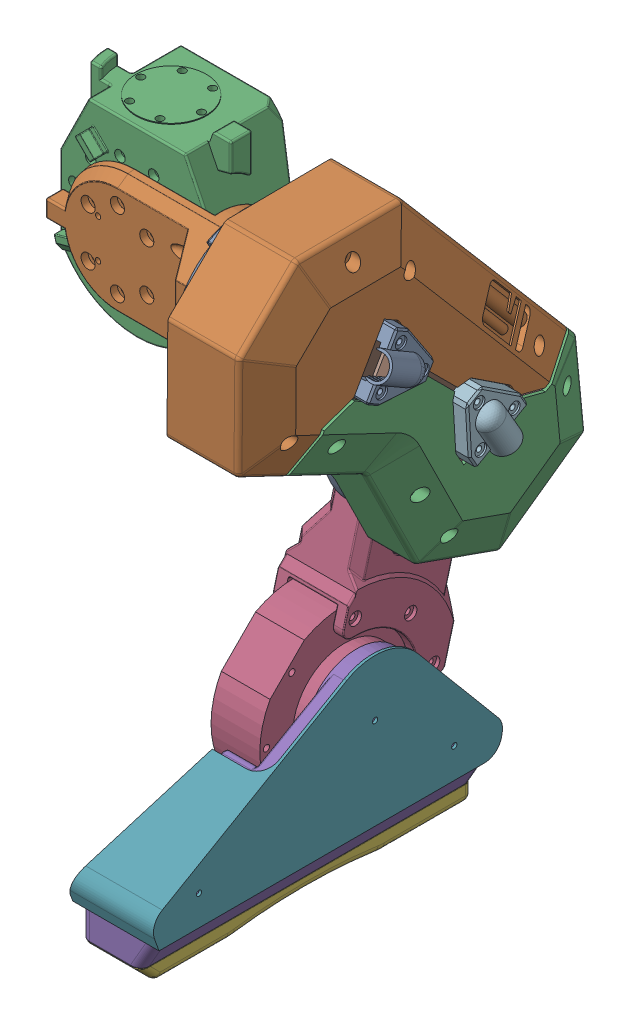
SolidWorks assembly 左腿, configuration 默认. Lengths in mm.
Overall size (184.93 459.26 275.12).
15 component instances, 12 part files, 51 mates.
Components (placement in the parent):
- 大腿left_pitch-1: 大腿left_pitch [默认] at (63 -62.5711 -79.7817) x (0 -0.707107 -0.707107) z (1 0 0) size (220 100.08 52.07)
- 大腿left_roll-1: 大腿left_roll [默认] at (63 -55.5 -2) x (0 0 1) z (-1 0 0) size (71.94 70 103.87)
- 大腿left_yaw-1: 大腿left_yaw [默认] at (0 -55.5 -53) size (99.54 110 58)
- 小腿left_pitch-1: 小腿left_pitch [默认] at (73.5 -140.3528 -86.8528) x (0 0.707107 0.707107) z (-1 0 0) size (144.22 133.76 40.34)
- 脚掌left_pitch-1: 脚掌left_pitch [默认] at (83.2 -422.4881 -168.8962) x (0 -0.619688 0.784849) z (1 0 0) size (169.64 143.55 45)
- 鞋底脚板-1: 鞋底脚板 [默认] at (71.4265 -40.6299 49.2728) x (0 -0.691677 0.722207) z (-1 0 0) size (136.26 135.6 33)
- 左脚鞋面壳-1: 左脚鞋面壳 [默认] at (83.2 -83.9006 112.4365) x (0 0 1) z (-1 0 0) size (198.24 84 49)
- A1电机模型-1: A1电机模型 [默认] at (107.05 -55.5 -2) x (0 0.5 0.866025) z (-1 0 0) size (92 92 49.05)
- A1电机模型-2: A1电机模型 [默认] at (0 -55.5 -44.05) x (0 -1 0) z (0 0 1) size (92 92 49.05)
- A1电机模型-3: A1电机模型 [默认] at (107.05 -140.3528 -86.8528) x (0 -0.866025 -0.5) z (-1 0 0) size (92 92 49.05)
- 大腿左穿线板2-1: 大腿左穿线板2 [默认] at (108 -76.8035 -65.5494) x (0 -0.707107 -0.707107) z (1 0 0) size (105.13 45.22 9)
- 大腿波纹管连接件-1: 大腿波纹管连接件 [默认] at (117 -129.9252 -80.9139) x (0 0.866025 0.5) z (1 0 0) size (35 34 17.5)
- 大腿波纹管连接件-2: 大腿波纹管连接件 [默认] at (117 -61.4389 -12.4276) x (0 -0.5 -0.866025) z (1 0 0) size (35 34 17.5)
- 左大腿外壳-1: 左大腿外壳 [默认] at (70.05 -125.3028 -488.7467) x (0 0.087156 0.996195) z (-1 0 0) size (207.48 194.95 50)
- Go2电机模型-1: Go2电机模型 [默认] at (39.8 -275.5824 -50.6181) x (0 -0.707107 -0.707107) z (1 0 0) size (92.5 96.5 42.4)
Mates (geometry in assembly coordinates):
- 同心2: concentric aligned: cylinder of 大腿left_yaw-1 through (0 -55.5 0) axis (0 0 -1) radius 49; cylinder of A1电机模型-2 through (0 -55.5 -13.5) axis (0 0 -1) radius 46
- 重合3: coincident anti-aligned: plane of 大腿left_yaw-1 through (0 -55.5 -10.5) normal (0 0 -1); plane of A1电机模型-2 through (0 -55.5 -10.5) normal (0 0 1)
- 重合4: coincident aligned: plane of 大腿left_yaw-1 through (-5.5 0 -25) normal (0 1 0)
- 重合5: coincident aligned: plane of A1电机模型-2 through (0 -55.5 0) normal (0 0 1)
- 对称2: symmetric aligned: plane of A1电机模型-2 through (5 -55.5 -49.05) normal (1 0 0); plane of A1电机模型-2 through (-5 -55.5 -49.05) normal (-1 0 0)
- 重合6: coincident anti-aligned: plane of 大腿left_roll-1 through (0 -55.5 0) normal (0 0 -1); plane of A1电机模型-2 through (0 -55.5 0) normal (0 0 1)
- 同心3: concentric: sphere of 大腿left_roll-1; cylinder of 大腿left_yaw-1 through (0 -55.5 0) axis (0 0 -1) radius 49
- 同心4: concentric anti-aligned: cylinder of 大腿left_pitch-1 through (108 -55.5 -2) axis (-1 0 0) radius 50; cylinder of A1电机模型-1 through (76.5 -55.5 -2) axis (1 0 0) radius 46
- 重合7: coincident anti-aligned: plane of 大腿left_pitch-1 through (73.5 -55.5 -2) normal (1 0 0); plane of A1电机模型-1 through (73.5 -55.5 -2) normal (-1 0 0)
- 同心5: concentric anti-aligned: cylinder of 大腿left_pitch-1 through (108 -55.5 -2) axis (-1 0 0) radius 50; cylinder of 大腿left_roll-1 through (58 -55.5 -2) axis (1 0 0) radius 32.5
- 重合8: coincident aligned: plane of A1电机模型-1 through (107.05 -55.5 -2) normal (1 0 0); plane of A1电机模型-3 through (107.05 -140.3528 -86.8528) normal (1 0 0)
- 同心7: concentric anti-aligned: cylinder of 大腿left_pitch-1 through (108 -140.3528 -86.8528) axis (-1 0 0) radius 50; cylinder of A1电机模型-3 through (76.5 -140.3528 -86.8528) axis (1 0 0) radius 46
- 重合9: coincident anti-aligned: plane of 小腿left_pitch-1 through (63 -140.3528 -86.8528) normal (1 0 0); plane of A1电机模型-3 through (63 -140.3528 -86.8528) normal (-1 0 0)
- 同心8: concentric anti-aligned: cylinder of 大腿left_pitch-1 through (108 -140.3528 -86.8528) axis (-1 0 0) radius 50; cylinder of 小腿left_pitch-1 through (33.5 -140.3528 -86.8528) axis (1 0 0) radius 35
- 同心9: concentric aligned: cylinder of 小腿left_pitch-1 through (39.8 -275.5824 -50.6181) axis (1 0 0) radius 50.5; cylinder of M8010电机2-2 through (54.15 -222.0467 -42.2576) axis (1 0 0) radius 48.25
- 重合10: coincident anti-aligned: plane of 小腿left_pitch-1 through (67.5 -275.5824 -50.6181) normal (-1 0 0); plane of M8010电机2-2 through (67.5 -238.9819 -88.9907) normal (1 0 0)
- 同心10: concentric aligned: cylinder of 小腿left_pitch-1 through (43.5 -275.5824 -93.1181) axis (-1 0 0) radius 1.75; cylinder of M8010电机2-2 through (42.05 -233.2825 -83.2456) axis (-1 0 0) radius 1.45
- 重合11: coincident anti-aligned: plane of 脚掌left_pitch-1 through (74.2 -422.4881 89.4581) normal (-1 0 0); plane of M8010电机2-2 through (74.1 -277.008 -69.4285) normal (1 0 0)
- 同心11: concentric anti-aligned: cylinder of 脚掌left_pitch-1 through (38.2 -275.5824 -50.6181) axis (1 0 0) radius 30; cylinder of M8010电机2-2 through (68.9 -222.0467 -42.2576) axis (-1 0 0) radius 29.5
- 重合12: coincident anti-aligned: plane of 大腿left_roll-1 through (63 -55.5 -2) normal (1 0 0); plane of A1电机模型-1 through (63 -55.5 -2) normal (-1 0 0)
- 重合13: coincident anti-aligned: plane of 脚掌left_pitch-1 through (83.2 -422.4881 -168.8962) normal (1 0 0); plane of 左脚鞋面壳-1 through (83.2 -275.5824 -50.6181) normal (-1 0 0)
- 同心12: concentric aligned: cylinder of 脚掌left_pitch-1 through (78.2 -310.5824 49.3819) axis (1 0 0) radius 2.5; cylinder of 左脚鞋面壳-1 through (82.7 -310.5824 49.3819) axis (1 0 0) radius 1.5
- 同心13: concentric aligned: cylinder of 脚掌left_pitch-1 through (38.2 -275.5824 -50.6181) axis (1 0 0) radius 2.5; cylinder of 左脚鞋面壳-1 through (37.2 -275.5824 -50.6181) axis (1 0 0) radius 1.5
- 重合14: coincident anti-aligned: plane of 脚掌left_pitch-1 through (71.653 -345.5824 89.4581) normal (0 -1 0); plane of 鞋底脚板-1 through (38.4265 -345.5824 -119.1489) normal (0 1 0)
- 同心14: concentric aligned: cylinder of 脚掌left_pitch-1 through (54.9265 -285.5824 38.8511) axis (0 -1 0) radius 1.55; cylinder of 鞋底脚板-1 through (54.9265 -251.1705 38.8511) axis (0 -1 0) radius 1.55
- 同心15: concentric aligned: cylinder of 脚掌left_pitch-1 through (54.9265 -285.5824 -99.1489) axis (0 -1 0) radius 1.55; cylinder of 鞋底脚板-1 through (54.9265 -251.1705 -99.1489) axis (0 -1 0) radius 1.55
- 重合16: coincident anti-aligned: plane of 大腿left_pitch-1 through (108 -55.5 -2) normal (1 0 0); plane of 大腿左穿线板2-1 through (108 -76.8035 -65.5494) normal (-1 0 0)
- 同心20: concentric aligned: cylinder of A1电机模型-1 through (108.05 -61.0474 -44.1364) axis (-1 0 0) radius 1.75; cylinder of 大腿左穿线板2-1 through (117 -61.0474 -44.1364) axis (-1 0 0) radius 1.75
- 同心21: concentric aligned: cylinder of A1电机模型-1 through (108.05 -89.2175 -27.8724) axis (-1 0 0) radius 1.75; cylinder of 大腿左穿线板2-1 through (117 -89.2175 -27.8724) axis (-1 0 0) radius 1.75
- 同心22: concentric aligned: cylinder of A1电机模型-3 through (108.05 -98.2164 -81.3055) axis (-1 0 0) radius 1.75; cylinder of 大腿左穿线板2-1 through (117 -98.2164 -81.3055) axis (-1 0 0) radius 1.75
- 平行1: parallel: line of 大腿left_roll-1 through (57.5 -21.2669 5.0854) axis (-1 0 0); plane of 大腿left_yaw-1 through (-5.5 0 -25) normal (0 1 0)
- 平行2: parallel anti-aligned: plane of 大腿left_yaw-1 through (-5.5 0 -25) normal (0 1 0); plane of 鞋底脚板-1 through (38.4265 -355.5824 69.8511) normal (0 -1 0)
- 重合17: coincident anti-aligned: plane of 大腿左穿线板2-1 through (117 -76.8035 -65.5494) normal (1 0 0); plane of 大腿波纹管连接件-1 through (117 -129.9252 -80.9139) normal (-1 0 0)
- 同心23: concentric aligned: cylinder of 大腿左穿线板2-1 through (117 -130.2291 -68.3876) axis (-1 0 0) radius 1.5; cylinder of 大腿波纹管连接件-1 through (127 -130.2291 -68.3876) axis (-1 0 0) radius 1.5
- 同心24: concentric aligned: cylinder of 大腿左穿线板2-1 through (117 -106.5425 -67.4139) axis (-1 0 0) radius 1.5; cylinder of 大腿波纹管连接件-1 through (127 -106.5425 -67.4139) axis (-1 0 0) radius 1.5
- 同心25: concentric aligned: cylinder of 大腿左穿线板2-1 through (117 -54.9126 -23.1237) axis (-1 0 0) radius 1.5; cylinder of 大腿波纹管连接件-2 through (127 -54.9126 -23.1237) axis (-1 0 0) radius 1.5
- 同心26: concentric aligned: cylinder of 大腿左穿线板2-1 through (117 -73.9652 -12.1237) axis (-1 0 0) radius 1.5; cylinder of 大腿波纹管连接件-2 through (127 -73.9652 -12.1237) axis (-1 0 0) radius 1.5
- 重合18: coincident aligned: plane of 大腿波纹管连接件-1 through (127 -129.9252 -80.9139) normal (1 0 0); plane of 大腿波纹管连接件-2 through (127 -61.4389 -12.4276) normal (1 0 0)
- 重合19: coincident anti-aligned: plane of A1电机模型-1 through (108.05 -13.3636 -7.5474) normal (1 0 0); plane of 左大腿外壳-1 through (108.05 -29.6276 -35.7175) normal (-1 0 0)
- 同心27: concentric aligned: cylinder of A1电机模型-1 through (108.05 -13.3636 -7.5474) axis (-1 0 0) radius 1.75; cylinder of 左大腿外壳-1 through (120.05 -13.3636 -7.5474) axis (-1 0 0) radius 4
- 同心29: concentric aligned: cylinder of A1电机模型-1 through (108.05 -81.3724 31.7175) axis (-1 0 0) radius 1.75; cylinder of 左大腿外壳-1 through (120.05 -81.3724 31.7175) axis (-1 0 0) radius 4
- 重合20: coincident anti-aligned: plane of 脚掌left_pitch-1 through (74.2 -422.4881 89.4581) normal (-1 0 0); plane of Go2电机模型-1 through (74.2 -275.5824 -50.6181) normal (1 0 0)
- 同心30: concentric anti-aligned: cylinder of 小腿left_pitch-1 through (39.8 -275.5824 -50.6181) axis (1 0 0) radius 50.5; cylinder of Go2电机模型-1 through (67.5 -275.5824 -50.6181) axis (-1 0 0) radius 48.25
- 同心31: concentric anti-aligned: cylinder of 脚掌left_pitch-1 through (38.2 -275.5824 -50.6181) axis (1 0 0) radius 30; cylinder of Go2电机模型-1 through (74.2 -275.5824 -50.6181) axis (-1 0 0) radius 29.5
- 同心32: concentric aligned: cylinder of 小腿left_pitch-1 through (43.5 -233.0824 -50.6181) axis (-1 0 0) radius 1.75; cylinder of Go2电机模型-1 through (44.8 -233.0824 -50.6181) axis (-1 0 0) radius 1.75
- 重合21: coincident anti-aligned: plane of 小腿left_pitch-1 through (67.5 -275.5824 -50.6181) normal (-1 0 0); plane of Go2电机模型-1 through (67.5 -275.5824 -50.6181) normal (1 0 0)
- 角度1: planar angle = 0.523599 rad anti-aligned: plane of 大腿left_roll-1 through (52 -50.5 -34.1131) normal (0 1 0); plane of 大腿left_pitch-1 through (59 -19.2572 -54.7744) normal (0 -0.866025 -0.5)
- 角度2: planar angle = 0.785398 rad anti-aligned: plane of 小腿left_pitch-1 through (33.5 -115.6041 -111.6016) normal (0 0.707107 -0.707107); plane of 大腿left_pitch-1 through (56 -104.9975 -122.2082) normal (0 -1 0)
- 重合22: coincident anti-aligned: plane of A1电机模型-3 through (108.05 -134.8055 -128.9892) normal (1 0 0); plane of 左大腿外壳-1 through (108.05 -134.8055 -128.9892) normal (-1 0 0)
- 同心33: concentric aligned: cylinder of A1电机模型-3 through (108.05 -134.8055 -128.9892) axis (-1 0 0) radius 1.75; cylinder of 左大腿外壳-1 through (110.05 -134.8055 -128.9892) axis (-1 0 0) radius 1.75
- 同心34: concentric aligned: cylinder of A1电机模型-3 through (108.05 -174.0703 -60.9805) axis (-1 0 0) radius 1.75; cylinder of 左大腿外壳-1 through (110.05 -174.0703 -60.9805) axis (-1 0 0) radius 1.75
